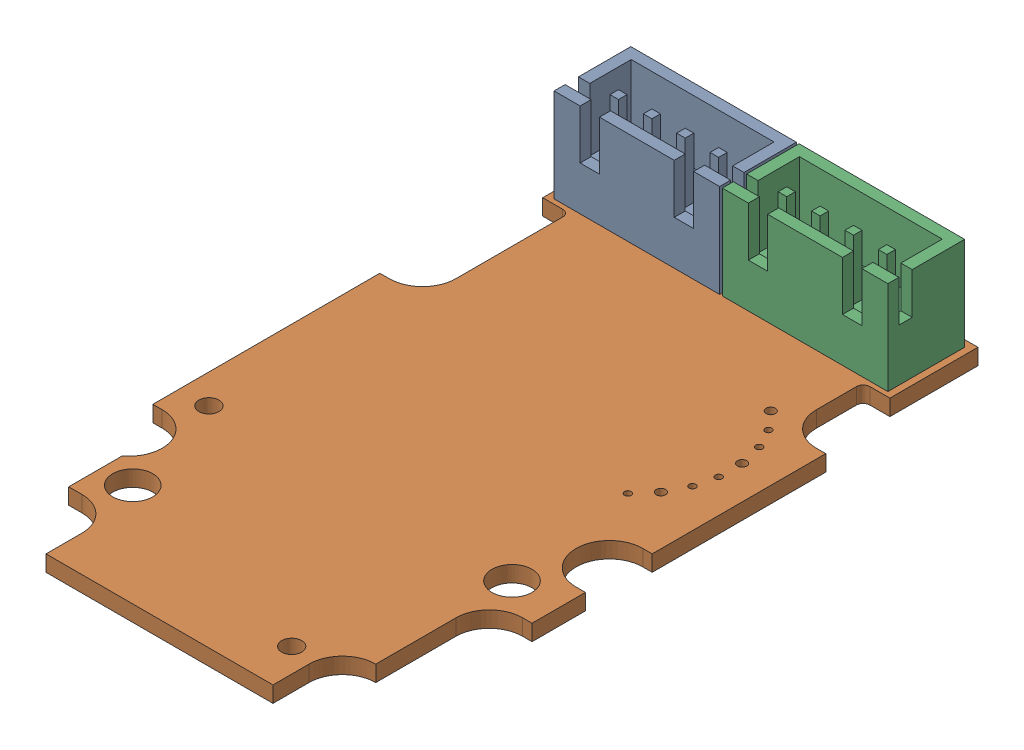
SolidWorks assembly 60K-メイン基板ASSY, configuration ﾃﾞﾌｫﾙﾄ. Lengths in mm.
Overall size (28.4 10.4 48.3).
3 component instances, 2 part files, 0 mates.
Components (placement in the parent):
- B4B-XH-A-1: B4B-XH-A [ﾃﾞﾌｫﾙﾄ] at (-6.2999 -27.7 -34.725) size (12.4 10.4 5.75)
- 60K-メイン基板-1: 60K-メイン基板 [ﾃﾞﾌｫﾙﾄ] at (0.0001 -28.9 0) x (-1 0 0) z (0 0 -1) size (28.4 2.7 48.3)
- B4B-XH-A-2: B4B-XH-A [ﾃﾞﾌｫﾙﾄ] at (6.3001 -27.7 -34.725) size (12.4 10.4 5.75)
